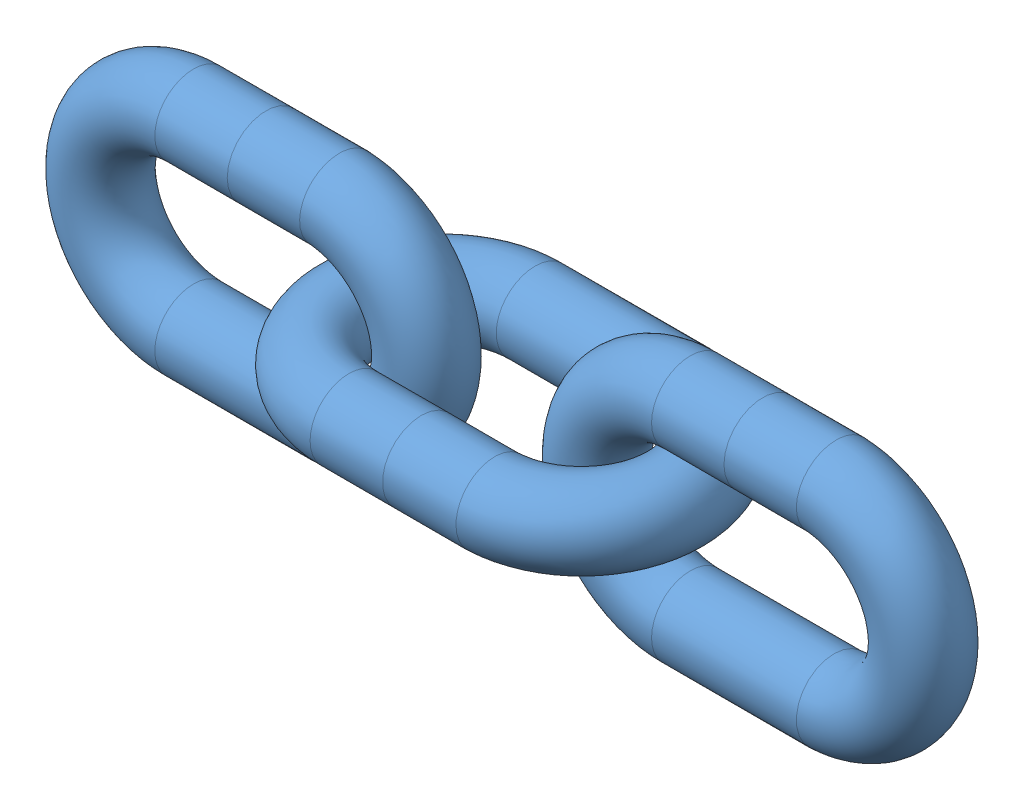
SolidWorks assembly Łańcuch10-3og, configuration Domyślna. Lengths in mm.
Overall size (116.06 34 34).
3 component instances, 1 part files, 4 mates.
Components (placement in the parent):
- ogniwo10-1: ogniwo10 [Domyślna] at origin size (52.02 34 10)
- ogniwo10-2: ogniwo10 [Domyślna] at (64.037 0 0) size (52.02 34 10)
- ogniwo10-3: ogniwo10 [Domyślna] at (32.0185 0 0) x (1 0 0) z (0 -1 0) size (52.02 34 10)
Mates (geometry in assembly coordinates):
- Wspólnie1: coincident aligned: plane of ? through (58.604 0.1285 0) normal (0 0 1)
- Wspólnie2: coincident anti-aligned: plane of ogniwo10-3 through (32.0185 0 0) normal (0 -1 0); plane of assembly
- Wspólnie3: coincident: point of ogniwo10-1; point of ogniwo10-3
- Wspólnie4: coincident: point of ogniwo10-2; point of ogniwo10-3
